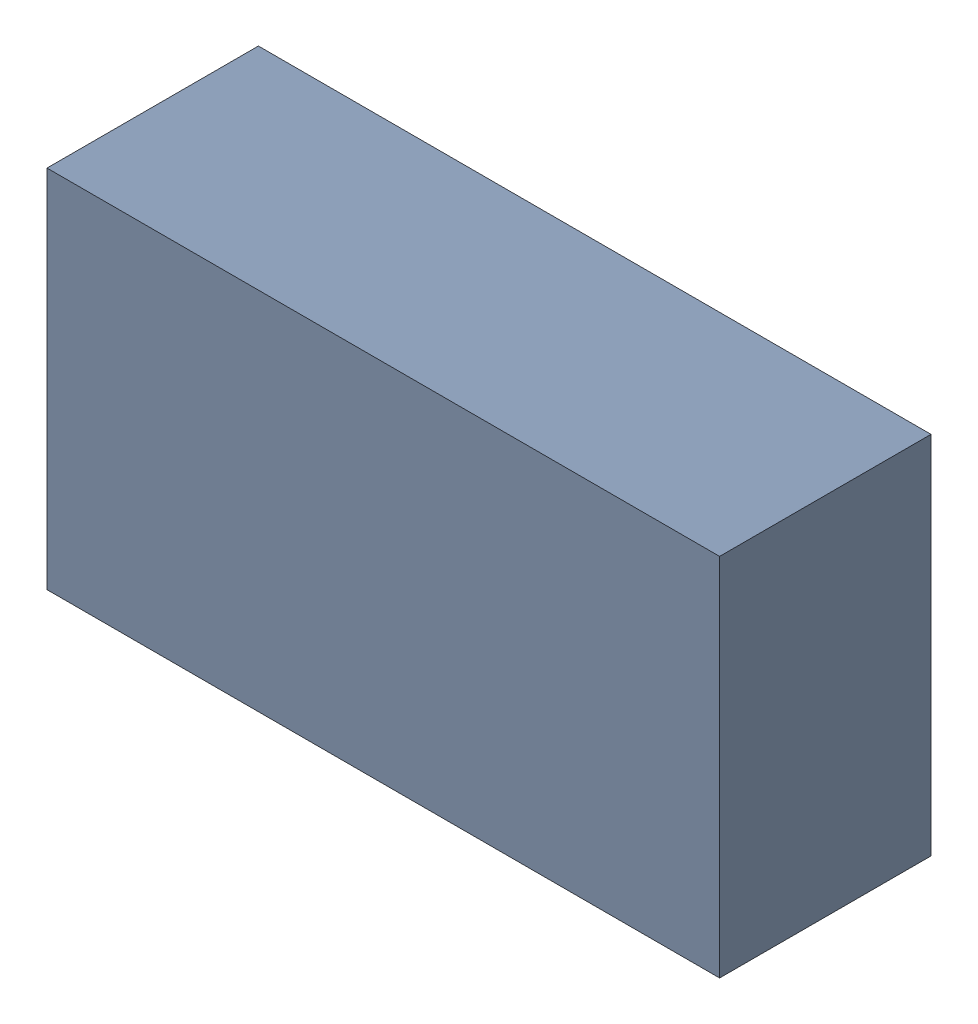
SolidWorks assembly L1_TDA1, configuration Standard. Lengths in mm.
Overall size (1.75 0.95 0.55).
2 component instances, 1 part files, 0 mates.
Components (placement in the parent):
- 885542648-1: 885542648 [Standard] at (0.78 56.04 0) size (1.75 0.95 0.55)
  - Extruded_19-1: Extruded_19 [Standard] at origin size (1.75 0.95 0.55)
